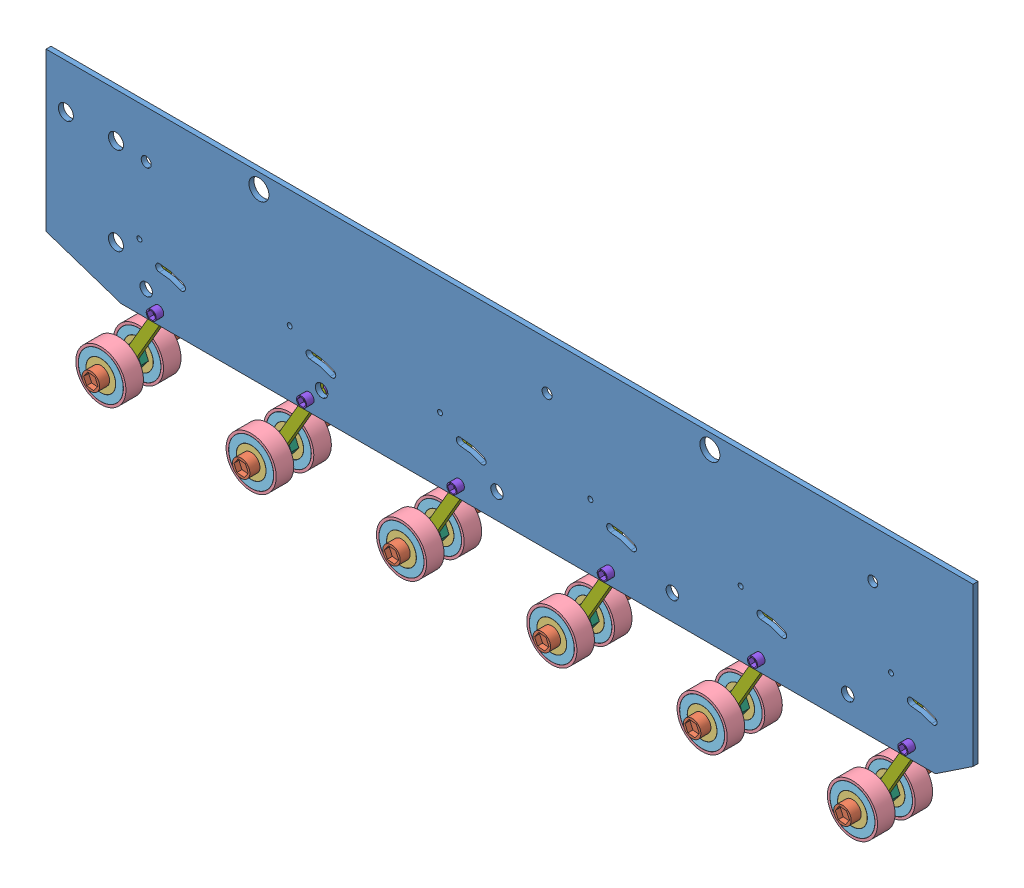
SolidWorks assembly 侧面装配体, configuration 默认. Lengths in mm.
Overall size (370 107.1 34).
91 component instances, 8 part files, 4 mates.
Components (placement in the parent):
- 板子-1: 板子 [默认] at (-4.8801 -10.8259 269) size (370 73 2)
- 下导轮-1: 下导轮 [默认] at (-171.2286 10.4942 246.4358) x (0.915314 0.40274 0) z (0.40274 -0.915314 0) size (47.59 34 44.61)
  - 下螺栓-1: 下螺栓 [默认] at (-13.5888 36.5642 40.1657) size (7 34 7)
  - 轴承-1: 轴承 [默认] at (-8.5233 19.0642 40.969) x (1 0 0) z (0 1 0) size (20 20 7)
    - 轴承内圈-1: 轴承内圈 [默认] at (-5.0655 0.8032 6.5) size (11.8 11.8 7)
    - 轴承外圈-1: 轴承外圈 [默认] at (-5.0655 0.8032 6.5) size (20 20 7)
    - 轴承中圈-1: 轴承中圈 [默认] at (-5.0655 0.8032 6.5) size (17.9 17.9 7)
  - 下部螺母-2: 下部螺母 [默认] at (-13.5888 25.5642 40.1657) x (1 0 0) z (0 -1 0) size (7.03 8.08 3.23)
  - 下部连接-1: 下部连接 [默认] at (-13.5888 20.5642 40.1657) x (0.808943 0 -0.587887) z (0 1 0) size (47.29 13.6 2)
  - 下部螺母-3: 下部螺母 [默认] at (-13.5888 20.5642 40.1657) x (1 0 0) z (0 -1 0) size (7.03 8.08 3.23)
  - 轴承-2: 轴承 [默认] at (-8.5233 4.0642 40.969) x (1 0 0) z (0 1 0) size (20 20 7)
    - 轴承内圈-1: 轴承内圈 [默认] at (-5.0655 0.8032 6.5) size (11.8 11.8 7)
    - 轴承外圈-1: 轴承外圈 [默认] at (-5.0655 0.8032 6.5) size (20 20 7)
    - 轴承中圈-1: 轴承中圈 [默认] at (-5.0655 0.8032 6.5) size (17.9 17.9 7)
  - 下部螺母-4: 下部螺母 [默认] at (-13.5888 10.5642 40.1657) x (1 0 0) z (0 -1 0) size (7.03 8.08 3.23)
- 螺栓3M-1: 螺栓3M [默认] at (-152.3801 -5.8259 274) x (-0.923728 -0.383049 0) z (0 0 -1) size (4 4 11)
- 螺栓3M-2: 螺栓3M [默认] at (-92.3801 -5.8259 274) x (-0.923728 -0.383049 0) z (0 0 -1) size (4 4 11)
- 螺栓3M-3: 螺栓3M [默认] at (-32.3801 -5.8259 274) x (-0.923728 -0.383049 0) z (0 0 -1) size (4 4 11)
- 螺栓3M-4: 螺栓3M [默认] at (27.6199 -5.8259 274) x (-0.923728 -0.383049 0) z (0 0 -1) size (4 4 11)
- 螺栓3M-5: 螺栓3M [默认] at (87.6199 -5.8259 274) x (-0.923728 -0.383049 0) z (0 0 -1) size (4 4 11)
- 螺栓3M-6: 螺栓3M [默认] at (147.6199 -5.8259 274) x (-0.923728 -0.383049 0) z (0 0 -1) size (4 4 11)
- 下导轮-2: 下导轮 [默认] at (-111.2286 10.4942 246.4358) x (0.915314 0.40274 0) z (0.40274 -0.915314 0) size (47.59 34 44.61)
  - 下螺栓-1: 下螺栓 [默认] at (-13.5888 36.5642 40.1657) size (7 34 7)
  - 轴承-1: 轴承 [默认] at (-8.5233 19.0642 40.969) x (1 0 0) z (0 1 0) size (20 20 7)
    - 轴承内圈-1: 轴承内圈 [默认] at (-5.0655 0.8032 6.5) size (11.8 11.8 7)
    - 轴承外圈-1: 轴承外圈 [默认] at (-5.0655 0.8032 6.5) size (20 20 7)
    - 轴承中圈-1: 轴承中圈 [默认] at (-5.0655 0.8032 6.5) size (17.9 17.9 7)
  - 下部螺母-2: 下部螺母 [默认] at (-13.5888 25.5642 40.1657) x (1 0 0) z (0 -1 0) size (7.03 8.08 3.23)
  - 下部连接-1: 下部连接 [默认] at (-13.5888 20.5642 40.1657) x (0.808943 0 -0.587887) z (0 1 0) size (47.29 13.6 2)
  - 下部螺母-3: 下部螺母 [默认] at (-13.5888 20.5642 40.1657) x (1 0 0) z (0 -1 0) size (7.03 8.08 3.23)
  - 轴承-2: 轴承 [默认] at (-8.5233 4.0642 40.969) x (1 0 0) z (0 1 0) size (20 20 7)
    - 轴承内圈-1: 轴承内圈 [默认] at (-5.0655 0.8032 6.5) size (11.8 11.8 7)
    - 轴承外圈-1: 轴承外圈 [默认] at (-5.0655 0.8032 6.5) size (20 20 7)
    - 轴承中圈-1: 轴承中圈 [默认] at (-5.0655 0.8032 6.5) size (17.9 17.9 7)
  - 下部螺母-4: 下部螺母 [默认] at (-13.5888 10.5642 40.1657) x (1 0 0) z (0 -1 0) size (7.03 8.08 3.23)
- 下导轮-3: 下导轮 [默认] at (-51.2286 10.4942 246.4358) x (0.915314 0.40274 0) z (0.40274 -0.915314 0) size (47.59 34 44.61)
  - 下螺栓-1: 下螺栓 [默认] at (-13.5888 36.5642 40.1657) size (7 34 7)
  - 轴承-1: 轴承 [默认] at (-8.5233 19.0642 40.969) x (1 0 0) z (0 1 0) size (20 20 7)
    - 轴承内圈-1: 轴承内圈 [默认] at (-5.0655 0.8032 6.5) size (11.8 11.8 7)
    - 轴承外圈-1: 轴承外圈 [默认] at (-5.0655 0.8032 6.5) size (20 20 7)
    - 轴承中圈-1: 轴承中圈 [默认] at (-5.0655 0.8032 6.5) size (17.9 17.9 7)
  - 下部螺母-2: 下部螺母 [默认] at (-13.5888 25.5642 40.1657) x (1 0 0) z (0 -1 0) size (7.03 8.08 3.23)
  - 下部连接-1: 下部连接 [默认] at (-13.5888 20.5642 40.1657) x (0.808943 0 -0.587887) z (0 1 0) size (47.29 13.6 2)
  - 下部螺母-3: 下部螺母 [默认] at (-13.5888 20.5642 40.1657) x (1 0 0) z (0 -1 0) size (7.03 8.08 3.23)
  - 轴承-2: 轴承 [默认] at (-8.5233 4.0642 40.969) x (1 0 0) z (0 1 0) size (20 20 7)
    - 轴承内圈-1: 轴承内圈 [默认] at (-5.0655 0.8032 6.5) size (11.8 11.8 7)
    - 轴承外圈-1: 轴承外圈 [默认] at (-5.0655 0.8032 6.5) size (20 20 7)
    - 轴承中圈-1: 轴承中圈 [默认] at (-5.0655 0.8032 6.5) size (17.9 17.9 7)
  - 下部螺母-4: 下部螺母 [默认] at (-13.5888 10.5642 40.1657) x (1 0 0) z (0 -1 0) size (7.03 8.08 3.23)
- 下导轮-4: 下导轮 [默认] at (8.7714 10.4942 246.4358) x (0.915314 0.40274 0) z (0.40274 -0.915314 0) size (47.59 34 44.61)
  - 下螺栓-1: 下螺栓 [默认] at (-13.5888 36.5642 40.1657) size (7 34 7)
  - 轴承-1: 轴承 [默认] at (-8.5233 19.0642 40.969) x (1 0 0) z (0 1 0) size (20 20 7)
    - 轴承内圈-1: 轴承内圈 [默认] at (-5.0655 0.8032 6.5) size (11.8 11.8 7)
    - 轴承外圈-1: 轴承外圈 [默认] at (-5.0655 0.8032 6.5) size (20 20 7)
    - 轴承中圈-1: 轴承中圈 [默认] at (-5.0655 0.8032 6.5) size (17.9 17.9 7)
  - 下部螺母-2: 下部螺母 [默认] at (-13.5888 25.5642 40.1657) x (1 0 0) z (0 -1 0) size (7.03 8.08 3.23)
  - 下部连接-1: 下部连接 [默认] at (-13.5888 20.5642 40.1657) x (0.808943 0 -0.587887) z (0 1 0) size (47.29 13.6 2)
  - 下部螺母-3: 下部螺母 [默认] at (-13.5888 20.5642 40.1657) x (1 0 0) z (0 -1 0) size (7.03 8.08 3.23)
  - 轴承-2: 轴承 [默认] at (-8.5233 4.0642 40.969) x (1 0 0) z (0 1 0) size (20 20 7)
    - 轴承内圈-1: 轴承内圈 [默认] at (-5.0655 0.8032 6.5) size (11.8 11.8 7)
    - 轴承外圈-1: 轴承外圈 [默认] at (-5.0655 0.8032 6.5) size (20 20 7)
    - 轴承中圈-1: 轴承中圈 [默认] at (-5.0655 0.8032 6.5) size (17.9 17.9 7)
  - 下部螺母-4: 下部螺母 [默认] at (-13.5888 10.5642 40.1657) x (1 0 0) z (0 -1 0) size (7.03 8.08 3.23)
- 下导轮-5: 下导轮 [默认] at (68.7714 10.4942 246.4358) x (0.915314 0.40274 0) z (0.40274 -0.915314 0) size (47.59 34 44.61)
  - 下螺栓-1: 下螺栓 [默认] at (-13.5888 36.5642 40.1657) size (7 34 7)
  - 轴承-1: 轴承 [默认] at (-8.5233 19.0642 40.969) x (1 0 0) z (0 1 0) size (20 20 7)
    - 轴承内圈-1: 轴承内圈 [默认] at (-5.0655 0.8032 6.5) size (11.8 11.8 7)
    - 轴承外圈-1: 轴承外圈 [默认] at (-5.0655 0.8032 6.5) size (20 20 7)
    - 轴承中圈-1: 轴承中圈 [默认] at (-5.0655 0.8032 6.5) size (17.9 17.9 7)
  - 下部螺母-2: 下部螺母 [默认] at (-13.5888 25.5642 40.1657) x (1 0 0) z (0 -1 0) size (7.03 8.08 3.23)
  - 下部连接-1: 下部连接 [默认] at (-13.5888 20.5642 40.1657) x (0.808943 0 -0.587887) z (0 1 0) size (47.29 13.6 2)
  - 下部螺母-3: 下部螺母 [默认] at (-13.5888 20.5642 40.1657) x (1 0 0) z (0 -1 0) size (7.03 8.08 3.23)
  - 轴承-2: 轴承 [默认] at (-8.5233 4.0642 40.969) x (1 0 0) z (0 1 0) size (20 20 7)
    - 轴承内圈-1: 轴承内圈 [默认] at (-5.0655 0.8032 6.5) size (11.8 11.8 7)
    - 轴承外圈-1: 轴承外圈 [默认] at (-5.0655 0.8032 6.5) size (20 20 7)
    - 轴承中圈-1: 轴承中圈 [默认] at (-5.0655 0.8032 6.5) size (17.9 17.9 7)
  - 下部螺母-4: 下部螺母 [默认] at (-13.5888 10.5642 40.1657) x (1 0 0) z (0 -1 0) size (7.03 8.08 3.23)
- 下导轮-6: 下导轮 [默认] at (128.7714 10.4942 246.4358) x (0.915314 0.40274 0) z (0.40274 -0.915314 0) size (47.59 34 44.61)
  - 下螺栓-1: 下螺栓 [默认] at (-13.5888 36.5642 40.1657) size (7 34 7)
  - 轴承-1: 轴承 [默认] at (-8.5233 19.0642 40.969) x (1 0 0) z (0 1 0) size (20 20 7)
    - 轴承内圈-1: 轴承内圈 [默认] at (-5.0655 0.8032 6.5) size (11.8 11.8 7)
    - 轴承外圈-1: 轴承外圈 [默认] at (-5.0655 0.8032 6.5) size (20 20 7)
    - 轴承中圈-1: 轴承中圈 [默认] at (-5.0655 0.8032 6.5) size (17.9 17.9 7)
  - 下部螺母-2: 下部螺母 [默认] at (-13.5888 25.5642 40.1657) x (1 0 0) z (0 -1 0) size (7.03 8.08 3.23)
  - 下部连接-1: 下部连接 [默认] at (-13.5888 20.5642 40.1657) x (0.808943 0 -0.587887) z (0 1 0) size (47.29 13.6 2)
  - 下部螺母-3: 下部螺母 [默认] at (-13.5888 20.5642 40.1657) x (1 0 0) z (0 -1 0) size (7.03 8.08 3.23)
  - 轴承-2: 轴承 [默认] at (-8.5233 4.0642 40.969) x (1 0 0) z (0 1 0) size (20 20 7)
    - 轴承内圈-1: 轴承内圈 [默认] at (-5.0655 0.8032 6.5) size (11.8 11.8 7)
    - 轴承外圈-1: 轴承外圈 [默认] at (-5.0655 0.8032 6.5) size (20 20 7)
    - 轴承中圈-1: 轴承中圈 [默认] at (-5.0655 0.8032 6.5) size (17.9 17.9 7)
  - 下部螺母-4: 下部螺母 [默认] at (-13.5888 10.5642 40.1657) x (1 0 0) z (0 -1 0) size (7.03 8.08 3.23)
Mates (geometry in assembly coordinates):
- 重合2: coincident: plane of assembly; plane of assembly; plane of 板子-1 through (-4.8801 -10.8259 269) normal (0 0 -1); plane of 下导轮-1/下部连接-1 through (-152.3801 -5.8259 269) normal (0 0 1)
- 同心1: concentric: cylinder of assembly; cylinder of assembly; cylinder of 板子-1 through (-152.3801 -5.8259 269) axis (0 0 1) radius 1.5; cylinder of 下导轮-1/下部连接-1 through (-152.3801 -5.8259 267) axis (0 0 1) radius 1.5
- 重合3: coincident: plane of assembly; plane of assembly; plane of 板子-1 through (-4.8801 -10.8259 271) normal (0 0 1); plane of 螺栓3M-1 through (-152.3801 -5.8259 271) normal (0 0 -1)
- 同心2: concentric: cylinder of assembly; cylinder of assembly; cylinder of 板子-1 through (-152.3801 -5.8259 269) axis (0 0 1) radius 1.5; cylinder of 螺栓3M-1 through (-152.3801 -5.8259 263) axis (0 0 1) radius 1.5
